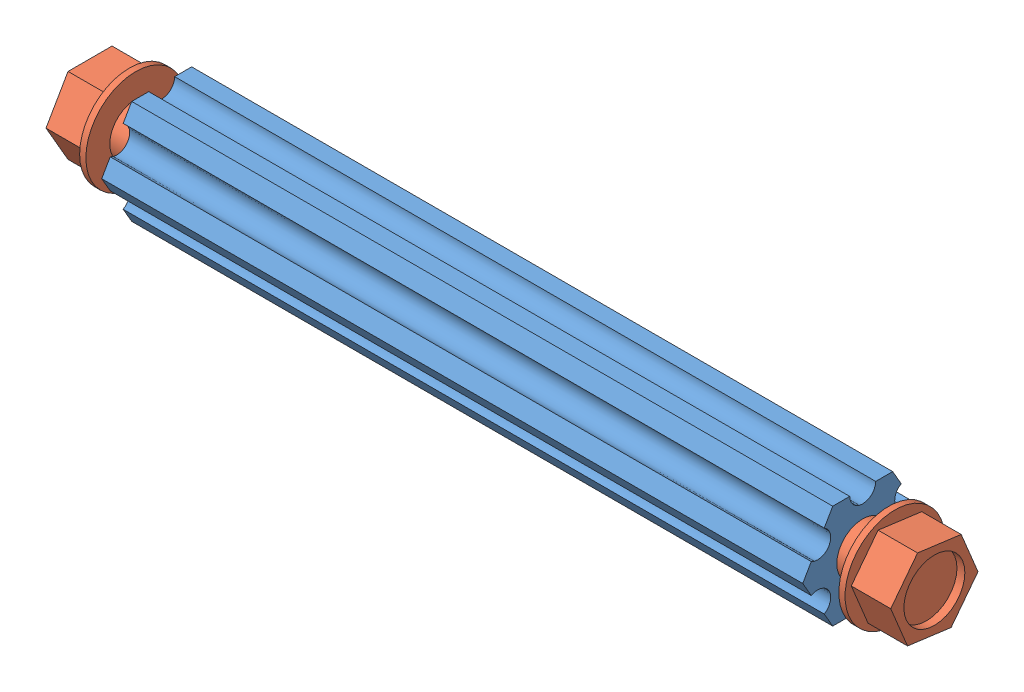
SolidWorks assembly Churro 3375 and Screws, configuration Default. Lengths in mm.
Overall size (103.25 15.92 15.92).
3 component instances, 2 part files, 4 mates.
Components (placement in the parent):
- Churro 3375-1: Churro 3375 [Default] at (110.2195 17.3332 -43.5379) x (0 0 1) z (-1 0 0) size (14.66 12.7 85.72)
- hex washer head tapping screw_ai-1: hex washer head tapping screw_ai [FHTS 0.25-20-G-0.75-C] at (21.3195 17.3332 -43.5379) size (24.64 12.19 12.19)
- hex washer head tapping screw_ai-2: hex washer head tapping screw_ai [FHTS 0.25-20-G-0.75-C] at (113.3945 17.3332 -43.5379) x (-1 0 0) z (0 -0.924225 -0.381849) size (24.64 12.19 12.19)
Mates (geometry in assembly coordinates):
- Concentric1: concentric anti-aligned: cylinder of Churro 3375-1 through (24.4945 17.3332 -43.5379) axis (1 0 0) radius 2.9337; cylinder of hex washer head tapping screw_ai-1 through (21.3195 17.3332 -43.5379) axis (-1 0 0) radius 3.175
- Concentric2: concentric aligned: cylinder of Churro 3375-1 through (24.4945 17.3332 -43.5379) axis (1 0 0) radius 2.9337; cylinder of hex washer head tapping screw_ai-2 through (113.3945 17.3332 -43.5379) axis (1 0 0) radius 3.175
- Distance1: distance = 3.175 mm anti-aligned: plane of hex washer head tapping screw_ai-1 through (21.3195 20.5082 -43.5379) normal (1 0 0); plane of Churro 3375-1 through (24.4945 20.5082 -38.0386) normal (-1 0 0)
- Distance2: distance = 3.175 mm anti-aligned: plane of hex washer head tapping screw_ai-2 through (113.3945 18.5456 -46.4723) normal (-1 0 0); plane of Churro 3375-1 through (110.2195 20.5082 -38.0386) normal (1 0 0)
